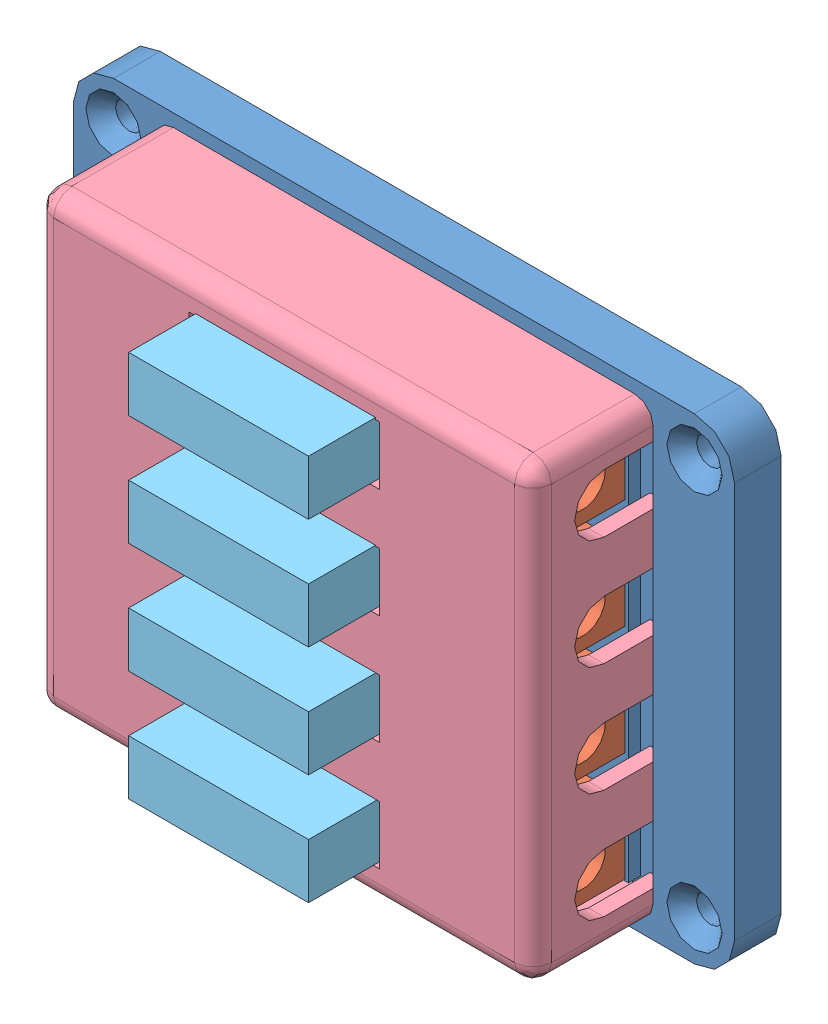
SolidWorks assembly Maxi Fuse Block, configuration Default. Lengths in mm.
Overall size (107.5 77.5 38).
27 component instances, 6 part files, 0 mates.
Components (placement in the parent):
- Maxi Fuse Block - Base-1: Maxi Fuse Block - Base [Default] at origin size (107.5 77.5 19.5)
- Maxi Fuse Block - Terminal-1: Maxi Fuse Block - Terminal [Default] at (26.42 -26.73 16.2) x (1 0 0) z (0 -1 0) size (28 19.9 11.5)
- Maxi Fuse Block - Terminal-2: Maxi Fuse Block - Terminal [Default] at (-26.42 -26.73 16.2) x (-1 0 0) z (0 1 0) size (28 19.9 11.5)
- Maxi Fuse Block - Terminal-3: Maxi Fuse Block - Terminal [Default] at (26.42 -8.91 16.2) x (1 0 0) z (0 -1 0) size (28 19.9 11.5)
- Maxi Fuse Block - Terminal-4: Maxi Fuse Block - Terminal [Default] at (-26.42 -8.91 16.2) x (-1 0 0) z (0 1 0) size (28 19.9 11.5)
- Maxi Fuse Block - Terminal-5: Maxi Fuse Block - Terminal [Default] at (26.42 8.91 16.2) x (1 0 0) z (0 -1 0) size (28 19.9 11.5)
- Maxi Fuse Block - Terminal-6: Maxi Fuse Block - Terminal [Default] at (-26.42 8.91 16.2) x (-1 0 0) z (0 1 0) size (28 19.9 11.5)
- Maxi Fuse Block - Terminal-7: Maxi Fuse Block - Terminal [Default] at (26.42 26.73 16.2) x (1 0 0) z (0 -1 0) size (28 19.9 11.5)
- Maxi Fuse Block - Terminal-8: Maxi Fuse Block - Terminal [Default] at (-26.42 26.73 16.2) x (-1 0 0) z (0 1 0) size (28 19.9 11.5)
- Maxi Fuse Block - Bottom Cover-1: Maxi Fuse Block - Bottom Cover [Default] at (4.987 4.269 1.62) x (-1 0 0) z (0 0 -1) size (84 68 1.62)
- Maxi Fuse Block - Top Cover-1: Maxi Fuse Block - Top Cover [Default] at (0 0 5.6) size (81 73.4 21.5)
- Maxi Fuse-1: Maxi Fuse [Default] at (0.245 -26.664 28.75) size (29.25 8.9 31.25)
  - Maxi Fuse - Body-1: Maxi Fuse - Body [Default] at origin size (29.25 8.9 18.5)
  - Maxi Fuse - Terminal-1: Maxi Fuse - Terminal [Default] at (10.625 0 -12.75) x (-1 0 0) z (0 1 0) size (8 18.5 0.86)
  - Maxi Fuse - Terminal-2: Maxi Fuse - Terminal [Default] at (-10.625 0 -12.75) x (1 0 0) z (0 -1 0) size (8 18.5 0.86)
- Maxi Fuse-2: Maxi Fuse [Default] at (0.245 -8.664 28.75) size (29.25 8.9 31.25)
  - Maxi Fuse - Body-1: Maxi Fuse - Body [Default] at origin size (29.25 8.9 18.5)
  - Maxi Fuse - Terminal-1: Maxi Fuse - Terminal [Default] at (10.625 0 -12.75) x (-1 0 0) z (0 1 0) size (8 18.5 0.86)
  - Maxi Fuse - Terminal-2: Maxi Fuse - Terminal [Default] at (-10.625 0 -12.75) x (1 0 0) z (0 -1 0) size (8 18.5 0.86)
- Maxi Fuse-3: Maxi Fuse [Default] at (0.245 9.336 28.75) size (29.25 8.9 31.25)
  - Maxi Fuse - Body-1: Maxi Fuse - Body [Default] at origin size (29.25 8.9 18.5)
  - Maxi Fuse - Terminal-1: Maxi Fuse - Terminal [Default] at (10.625 0 -12.75) x (-1 0 0) z (0 1 0) size (8 18.5 0.86)
  - Maxi Fuse - Terminal-2: Maxi Fuse - Terminal [Default] at (-10.625 0 -12.75) x (1 0 0) z (0 -1 0) size (8 18.5 0.86)
- Maxi Fuse-4: Maxi Fuse [Default] at (0.245 27.336 28.75) size (29.25 8.9 31.25)
  - Maxi Fuse - Body-1: Maxi Fuse - Body [Default] at origin size (29.25 8.9 18.5)
  - Maxi Fuse - Terminal-1: Maxi Fuse - Terminal [Default] at (10.625 0 -12.75) x (-1 0 0) z (0 1 0) size (8 18.5 0.86)
  - Maxi Fuse - Terminal-2: Maxi Fuse - Terminal [Default] at (-10.625 0 -12.75) x (1 0 0) z (0 -1 0) size (8 18.5 0.86)
